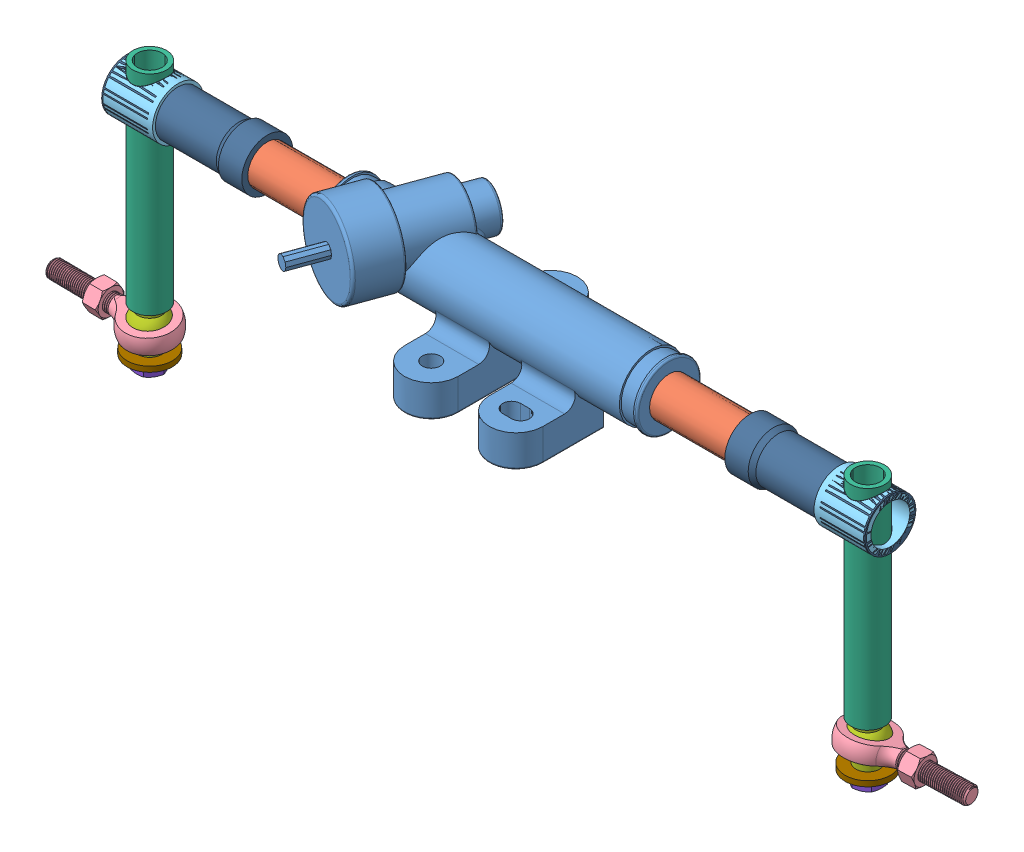
SolidWorks assembly steering assembly, configuration Default. Lengths in mm.
Overall size (513.18 167.92 106.9).
22 component instances, 12 part files, 36 mates.
Components (placement in the parent):
- prebuilt housing-1: prebuilt housing [Default] at (-22.0598 82.7728 134.0833) size (180 70.59 106.9)
- prebuilt rack-1: prebuilt rack [Default] at (207.9402 82.7728 134.0833) x (0 0.567124 0.823632) z (0 -0.823632 0.567124) size (22 304 22)
- extender-1: extender [Default] at (291.9402 82.7728 134.0833) x (0 0.924347 0.381554) z (0 -0.381554 0.924347) size (21.8 50.55 21.8)
- 3-8-24 swivel-3: 3-8-24 swivel [Default] at (-185.9718 28.0647 159.5712) x (-0.006612 0.105102 -0.994439) z (-0.023578 -0.994201 -0.10492) size (28.57 68.61 16.22)
- 3-8-24 swivel-4: 3-8-24 swivel [Default] at (322.7778 -82.9746 160.48) x (-0.097322 -0.214285 -0.971911) z (0.03722 0.97508 -0.21871) size (28.57 68.61 16.22)
- RackVertAdapt-1: RackVertAdapt [Default] at (-146.1968 82.7728 134.0833) size (28.57 28.57 28.57)
- RackVertAdapt-2: RackVertAdapt [Default] at (282.0773 82.7728 134.0833) x (-1 0 0) z (0 0 -1) size (28.57 28.57 28.57)
- Rackvertical-1: Rackvertical [Default] at (-133.4968 -16.996 134.0833) size (19.05 117.47 19.05)
- Rackvertical-2: Rackvertical [Default] at (269.3773 -16.996 134.0833) x (-0.951218 0 -0.308519) z (0.308519 0 -0.951218) size (19.05 117.47 19.05)
- BallSuper-Swivel  Joint Rod End6960T231_-1: BallSuper-Swivel  Joint Rod End6960T231_ [6960T231] at (-128.0548 -28.1085 115.8271) x (0.958328 0 0.28567) z (0 -1 0) size (20.64 20.64 22.23)
- BallSuper-Swivel  Joint Rod End6960T231_-2: BallSuper-Swivel  Joint Rod End6960T231_ [6960T231] at (287.2157 -28.1085 127.398) x (0.350934 0 0.9364) z (0 -1 0) size (20.64 20.64 22.23)
- 91257A659_Zinc Yellow-Chromate Plated Hex Head Screw-3: 91257A659_Zinc Yellow-Chromate Plated Hex Head Screw [91257A659] at (269.3773 -19.9805 134.0833) x (0 1 0) z (-0.577019 0 0.816731) size (57.6 16.5 14.29)
- 91257A659_Zinc Yellow-Chromate Plated Hex Head Screw-4: 91257A659_Zinc Yellow-Chromate Plated Hex Head Screw [91257A659] at (-133.4968 -19.9805 134.0833) x (0 1 0) z (-0.036356 0 0.999339) size (57.6 16.5 14.29)
- 3-8 98029A046_Black-Oxide Steel Oversized Washer-2: 3-8 98029A046_Black-Oxide Steel Oversized Washer [98029A046] at (-133.4968 -40.7133 134.0833) x (0.994656 0 -0.103243) z (0 1 0) size (25.4 25.4 2.98)
- 3-8 98029A046_Black-Oxide Steel Oversized Washer-3: 3-8 98029A046_Black-Oxide Steel Oversized Washer [98029A046] at (269.3773 -40.7133 134.0833) x (1 0 0) z (0 1 0) size (25.4 25.4 2.98)
- Part1^steering assembly-1: Part1^steering assembly [Default] at origin (virtual)
- GussetSteering-3: GussetSteering [Not Open] [Default] at (-96.2502 -463.7017 134.0833) x (0 -1 0) z (0 0 1) (suppressed, hidden)
- extender-3: extender [Default] at (-156.0598 82.7728 134.0833) x (0 -1 0) z (0 0 1) size (21.8 50.55 21.8)
- GussetSteering-4: GussetSteering [Not Open] [Default] at (252.5843 -463.7017 132.5593) x (0 -1 0) z (0 0 -1) (suppressed, hidden)
- GussetSteering-5: GussetSteering [Not Open] [Default] at (252.5843 -463.7017 132.5593) x (0 -1 0) z (0 0 -1) (suppressed, hidden)
- extender2-1: extender2 [Default] at (203.4389 82.7728 134.0833) size (78.98 28.57 28.57)
- extender2-2: extender2 [Default] at (-67.5584 82.7728 134.0833) x (-1 0 0) z (0 0 -1) size (78.98 28.57 28.57)
Mates (geometry in assembly coordinates):
- Concentric1: concentric anti-aligned: cylinder of prebuilt housing-1 through (157.9402 82.7728 134.0833) axis (-1 0 0) radius 11; cylinder of prebuilt rack-1 through (-72.0598 82.7728 134.0833) axis (1 0 0) radius 11
- Concentric8: concentric anti-aligned: circle of prebuilt rack-1; cylinder of extender-1 through (258.4802 82.7728 134.0833) axis (1 0 0) radius 10.9
- Concentric15: concentric aligned: cylinder of extender-1 through (258.4802 82.7728 134.0833) axis (1 0 0) radius 10.9; cylinder of RackVertAdapt-2 through (253.5023 82.7728 134.0833) axis (1 0 0) radius 10.9093
- Concentric19: concentric anti-aligned: circle of Rackvertical-1; circle of BallSuper-Swivel  Joint Rod End6960T231_-1
- Concentric22: concentric anti-aligned: circle of Rackvertical-2; circle of BallSuper-Swivel  Joint Rod End6960T231_-2
- Coincident16: coincident aligned: plane of Rackvertical-2 through (278.4376 -16.996 137.0219) normal (0 -1 0); circle of BallSuper-Swivel  Joint Rod End6960T231_-2
- Concentric23: concentric anti-aligned: circle of BallSuper-Swivel  Joint Rod End6960T231_-1; circle of 3-8 98029A046_Black-Oxide Steel Oversized Washer-2
- Coincident17: coincident anti-aligned: circle of BallSuper-Swivel  Joint Rod End6960T231_-1; plane of 3-8 98029A046_Black-Oxide Steel Oversized Washer-2 through (-133.4968 -39.221 134.0833) normal (0 1 0)
- Concentric25: concentric anti-aligned: circle of BallSuper-Swivel  Joint Rod End6960T231_-2; circle of 3-8 98029A046_Black-Oxide Steel Oversized Washer-3
- Coincident19: coincident anti-aligned: circle of BallSuper-Swivel  Joint Rod End6960T231_-2; plane of 3-8 98029A046_Black-Oxide Steel Oversized Washer-3 through (269.3773 -39.221 134.0833) normal (0 1 0)
- Coincident21: coincident aligned: plane of 91257A659_Zinc Yellow-Chromate Plated Hex Head Screw-3 through (261.8866 -42.2055 137.5379) normal (0 1 0); circle of 3-8 98029A046_Black-Oxide Steel Oversized Washer-3
- Concentric32: concentric anti-aligned: cylinder of 91257A659_Zinc Yellow-Chromate Plated Hex Head Screw-4 through (-133.4968 -42.2055 134.0833) axis (0 1 0) radius 4.7625; cylinder of 3-8 98029A046_Black-Oxide Steel Oversized Washer-2 through (-133.4968 -39.221 134.0833) axis (0 -1 0) radius 5.1562
- Coincident34: coincident: moEndPointRef_w of 91257A659_Zinc Yellow-Chromate Plated Hex Head Screw-4; plane of 3-8 98029A046_Black-Oxide Steel Oversized Washer-2 through (-133.4968 -42.2055 134.0833) normal (0 -1 0)
- Lock4: lock: unknown of RackVertAdapt-1; unknown of Rackvertical-1
- Lock6: lock: unknown of prebuilt rack-1; unknown of extender-1
- Lock7: lock: unknown of extender-1; unknown of RackVertAdapt-2
- Lock8: lock: unknown of RackVertAdapt-2; unknown of Rackvertical-2
- Lock9: lock: unknown of Rackvertical-2; unknown of BallSuper-Swivel  Joint Rod End6960T231_-2
- Concentric35: concentric anti-aligned: cylinder of 91257A659_Zinc Yellow-Chromate Plated Hex Head Screw-3 through (269.3773 -42.2055 134.0833) axis (0 1 0) radius 4.7625; cylinder of 3-8 98029A046_Black-Oxide Steel Oversized Washer-3 through (269.3773 -39.221 134.0833) axis (0 -1 0) radius 12.7
- Coincident54: coincident: point of 3-8-24 swivel-3; point of BallSuper-Swivel  Joint Rod End6960T231_-1
- Coincident56: coincident: point of 3-8-24 swivel-4; point of BallSuper-Swivel  Joint Rod End6960T231_-2
- Parallel1: parallel: line of Rackvertical-2 through (269.3773 100.479 134.0833) axis (0 -1 0)
- Coincident58: coincident aligned: plane of Rackvertical-1 through (-143.0218 -16.996 134.0833) normal (0 -1 0); circle of BallSuper-Swivel  Joint Rod End6960T231_-1
- Coincident73: coincident anti-aligned: plane of prebuilt rack-1 through (-72.0598 95.1403 107.9625) normal (-1 0 0); plane of extender-3 through (-72.0598 82.7728 134.0833) normal (1 0 0)
- Concentric36: concentric aligned: cylinder of prebuilt rack-1 through (-72.0598 82.7728 134.0833) axis (1 0 0) radius 11; cylinder of extender-3 through (-122.5998 82.7728 134.0833) axis (1 0 0) radius 10.9
- Concentric37: concentric anti-aligned: cylinder of RackVertAdapt-1 through (-117.6218 82.7728 134.0833) axis (-1 0 0) radius 14.2875; cylinder of extender-3 through (-122.5998 82.7728 134.0833) axis (1 0 0) radius 10.9
- Lock16: lock: unknown of RackVertAdapt-1; unknown of extender-3
- Lock19: lock: unknown of prebuilt rack-1; unknown of extender-3
- Parallel2: parallel aligned: line of Rackvertical-1 through (-133.4968 100.479 134.0833) axis (0 -1 0); line of Rackvertical-2 through (269.3773 100.479 134.0833) axis (0 -1 0)
- Perpendicular1: perpendicular: plane of prebuilt housing-1 through (57.9402 48.7728 100.5833) normal (0 -1 0); line of Rackvertical-1 through (-133.4968 100.479 134.0833) axis (0 -1 0)
- Coincident76: coincident: point of prebuilt rack-1; point of assembly
- Concentric39: concentric anti-aligned: line of Rackvertical-2 through (269.3773 100.479 134.0833) axis (0 -1 0); cylinder of extender2-1 through (269.3773 57.3728 134.0833) axis (0 1 0) radius 9.525
- Concentric38: concentric anti-aligned: cylinder of prebuilt rack-1 through (-72.0598 82.7728 134.0833) axis (1 0 0) radius 11; cylinder of extender2-1 through (203.4389 82.7728 134.0833) axis (-1 0 0) radius 14.2875
- Coincident78: coincident: point of prebuilt rack-1; point of assembly
- Concentric40: concentric anti-aligned: line of Rackvertical-1 through (-133.4968 100.479 134.0833) axis (0 -1 0); cylinder of extender2-2 through (-133.4968 57.3728 134.0833) axis (0 1 0) radius 9.525
- Concentric41: concentric aligned: cylinder of prebuilt rack-1 through (-72.0598 82.7728 134.0833) axis (1 0 0) radius 11; cylinder of extender2-2 through (-67.5584 82.7728 134.0833) axis (1 0 0) radius 14.2875
